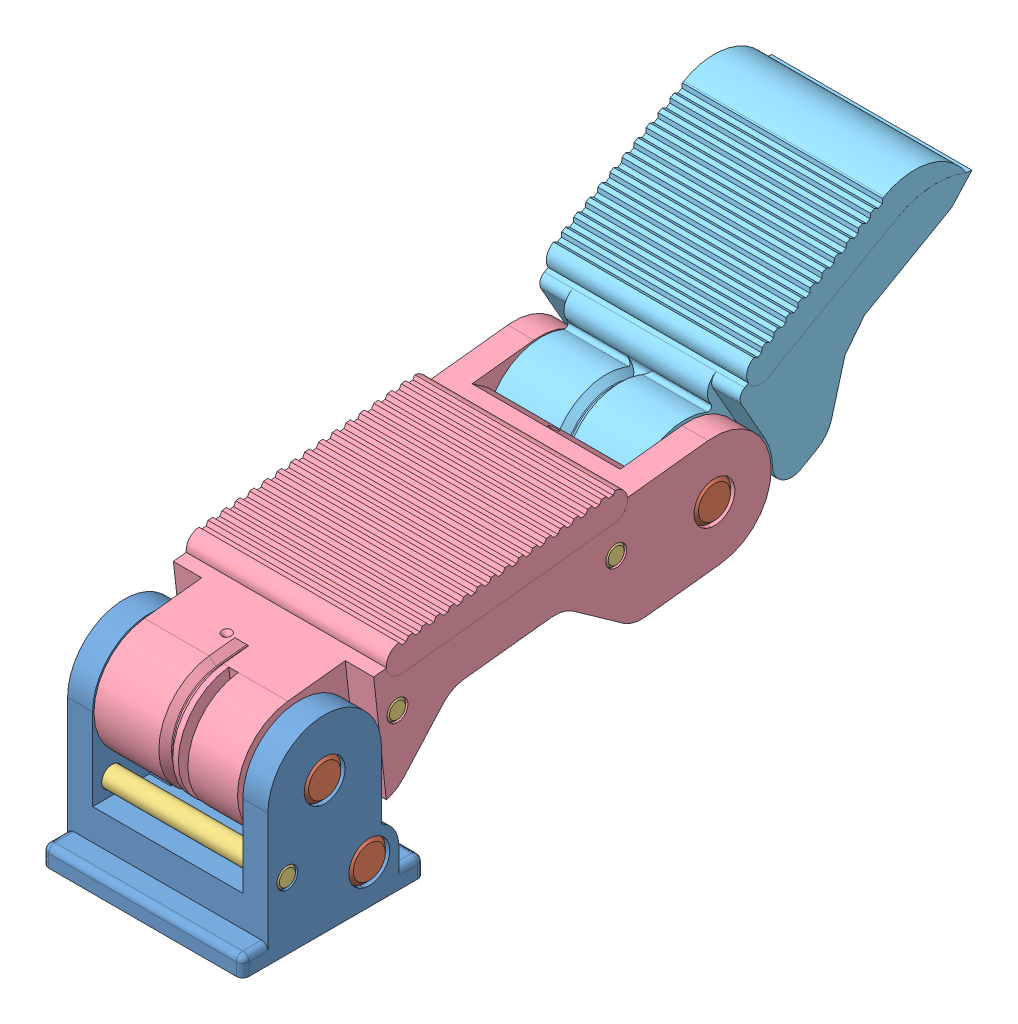
SolidWorks assembly block_finger_pp_t42, configuration Default. Lengths in mm.
Overall size (32.23 61.41 122.56).
15 component instances, 7 part files, 28 mates.
Components (placement in the parent):
- c1_t42-1: c1_t42 [Default] at origin size (31.75 29.94 28.75)
- 98381A544 D1-4 L5-4-1: 98381A544 D1-4 L5-4 [98381A544] at (0 20.9353 -30) size (31.75 6.35 6.35)
- 98381A544 D1-4 L5-4-2: 98381A544 D1-4 L5-4 [98381A544] at (0 6.175 -37.075) size (31.75 6.35 6.35)
- 98381A477 D1-8 L5-4-1: 98381A477 D1-8 L5-4 [98381A477] at (0 10.5228 -24.0875) size (31.75 3.17 3.17)
- t42_pp_A-1: t42_pp_A [Default] at (-0.325 20.9353 -30) x (1 0 0) z (0 -0.111473 0.993768) size (31.75 20.27 80.5)
- t42_pp_B-1: t42_pp_B [Default] at (-0.475 27.9023 -92.1105) x (1 0 0) z (0 -0.494638 0.869099) size (31.75 22.88 57.08)
- 98381A544 D1-4 L5-4-3: 98381A544 D1-4 L5-4 [98381A544] at (-0.325 27.9023 -92.1105) size (31.75 6.35 6.35)
- 98381A477 D1-8 L5-4-2: 98381A477 D1-8 L5-4 [98381A477] at (-0.325 24.4415 -41.8581) size (31.75 3.17 3.17)
- 98381A477 D1-8 L5-4-3: 98381A477 D1-8 L5-4 [98381A477] at (-0.325 28.3322 -76.5436) size (31.75 3.17 3.17)
- 93365A120 4-40 insert-1: 93365A120 4-40 insert [93365A120] at (-0.475 39.5312 -114.477) x (1 0 0) z (0 0.789576 -0.613653) size (4.37 3.82 4.37)
- 93365A120 4-40 insert-2: 93365A120 4-40 insert [93365A120] at (-0.475 22.7501 -101.253) x (-0.837169 0.270539 -0.475349) z (-0.546944 -0.414095 0.727583) size (4.37 3.82 4.37)
- 93365A120 4-40 insert-3: 93365A120 4-40 insert [93365A120] at (-0.325 17.6765 -81.6854) x (-0.837169 0.060969 -0.543535) z (-0.546944 -0.093321 0.831951) size (4.37 3.82 4.37)
- 91253A106 4-40 L1-4 countersunk-1: 91253A106 4-40 L1-4 countersunk [91253A106] at (-0.475 38.2295 -116.1519) x (1 0 0) z (0 -0.613653 -0.789576) size (6.48 6.48 6.63)
- 91253A106 4-40 L1-4 countersunk-2: 91253A106 4-40 L1-4 countersunk [91253A106] at (-0.475 20.9066 -102.3022) x (1 0 0) z (0 -0.869099 -0.494638) size (6.48 6.48 6.63)
- 91253A106 4-40 L1-4 countersunk-3: 91253A106 4-40 L1-4 countersunk [91253A106] at (-0.325 15.5685 -81.9219) x (1 0 0) z (0 -0.993768 -0.111473) size (6.48 6.48 6.63)
Mates (geometry in assembly coordinates):
- Concentric1: concentric aligned: cylinder of c1_t42-1 through (-15.875 20.9353 -30) axis (1 0 0) radius 3.25; cylinder of 98381A544 D1-4 L5-4-1 through (-15.875 20.9353 -30) axis (1 0 0) radius 3.175
- Coincident1: coincident aligned: plane of c1_t42-1 through (15.875 20.9353 -30) normal (1 0 0); plane of 98381A544 D1-4 L5-4-1 through (15.875 20.9353 -30) normal (1 0 0)
- Concentric2: concentric aligned: cylinder of c1_t42-1 through (-15.875 6.175 -37.075) axis (1 0 0) radius 3.25; cylinder of 98381A544 D1-4 L5-4-2 through (-15.875 6.175 -37.075) axis (1 0 0) radius 3.175
- Coincident2: coincident aligned: plane of c1_t42-1 through (15.875 20.9353 -30) normal (1 0 0); plane of 98381A544 D1-4 L5-4-2 through (15.875 6.175 -37.075) normal (1 0 0)
- Concentric3: concentric aligned: cylinder of c1_t42-1 through (-15.875 10.5228 -24.0875) axis (1 0 0) radius 1.6625; cylinder of 98381A477 D1-8 L5-4-1 through (-15.875 10.5228 -24.0875) axis (1 0 0) radius 1.5875
- Coincident3: coincident aligned: plane of c1_t42-1 through (15.875 20.9353 -30) normal (1 0 0); plane of 98381A477 D1-8 L5-4-1 through (15.875 10.5228 -24.0875) normal (1 0 0)
- Concentric4: concentric aligned: cylinder of 98381A544 D1-4 L5-4-1 through (-15.875 20.9353 -30) axis (1 0 0) radius 3.175; cylinder of t42_pp_A-1 through (-16.2 20.9353 -30) axis (1 0 0) radius 3.525
- Distance1: distance = 0.2 mm anti-aligned: plane of c1_t42-1 through (-11.9 20.9353 -30) normal (1 0 0); plane of t42_pp_A-1 through (-11.7 13.0113 -40.0962) normal (-1 0 0)
- Concentric5: concentric aligned: cylinder of t42_pp_A-1 through (-16.2 27.9023 -92.1105) axis (1 0 0) radius 3.25; cylinder of 98381A544 D1-4 L5-4-3 through (-16.2 27.9023 -92.1105) axis (1 0 0) radius 3.175
- Coincident5: coincident aligned: plane of t42_pp_A-1 through (15.55 20.9353 -30) normal (1 0 0); plane of 98381A544 D1-4 L5-4-3 through (15.55 27.9023 -92.1105) normal (1 0 0)
- Concentric6: concentric aligned: cylinder of t42_pp_B-1 through (-16.35 27.9023 -92.1105) axis (1 0 0) radius 3.525; cylinder of 98381A544 D1-4 L5-4-3 through (-16.2 27.9023 -92.1105) axis (1 0 0) radius 3.175
- Distance2: distance = 0.2 mm anti-aligned: plane of t42_pp_A-1 through (-12.05 27.9023 -92.1105) normal (1 0 0); plane of t42_pp_B-1 through (-11.85 27.9023 -92.1105) normal (-1 0 0)
- Concentric7: concentric aligned: cylinder of t42_pp_A-1 through (-16.2 24.4415 -41.8581) axis (1 0 0) radius 1.6625; cylinder of 98381A477 D1-8 L5-4-2 through (-16.2 24.4415 -41.8581) axis (1 0 0) radius 1.5875
- Coincident7: coincident aligned: plane of t42_pp_A-1 through (15.55 20.9353 -30) normal (1 0 0); plane of 98381A477 D1-8 L5-4-2 through (15.55 24.4415 -41.8581) normal (1 0 0)
- Concentric8: concentric aligned: cylinder of t42_pp_A-1 through (-16.2 28.3322 -76.5436) axis (1 0 0) radius 1.6625; cylinder of 98381A477 D1-8 L5-4-3 through (-16.2 28.3322 -76.5436) axis (1 0 0) radius 1.5875
- Coincident8: coincident aligned: plane of t42_pp_A-1 through (15.55 20.9353 -30) normal (1 0 0); plane of 98381A477 D1-8 L5-4-3 through (15.55 28.3322 -76.5436) normal (1 0 0)
- Concentric9: concentric aligned: cylinder of t42_pp_A-1 through (-0.325 22.1484 -81.1838) axis (0 -0.993768 -0.111473) radius 1.85; circle of 93365A120 4-40 insert-3
- Coincident9: coincident aligned: plane of t42_pp_A-1 through (15.55 11.9914 -31.0033) normal (0 -0.993768 -0.111473); plane of 93365A120 4-40 insert-3 through (-0.325 17.6765 -81.6854) normal (0 -0.993768 -0.111473)
- Concentric10: concentric aligned: cylinder of t42_pp_B-1 through (-0.475 26.2265 -99.2744) axis (0 -0.869099 -0.494638) radius 1.85; circle of 93365A120 4-40 insert-2
- Coincident10: coincident aligned: plane of t42_pp_B-1 through (15.4 20.0804 -96.5622) normal (0 -0.869099 -0.494638); plane of 93365A120 4-40 insert-2 through (-0.475 22.7501 -101.253) normal (0 -0.869099 -0.494638)
- Concentric11: concentric aligned: cylinder of t42_pp_B-1 through (-0.475 42.2926 -110.9239) axis (0 -0.613653 -0.789576) radius 1.85; circle of 93365A120 4-40 insert-1
- Coincident11: coincident aligned: plane of t42_pp_B-1 through (-21.35 41.5051 -116.0112) normal (0 -0.613653 -0.789576); plane of 93365A120 4-40 insert-1 through (-0.475 39.5312 -114.477) normal (0 -0.613653 -0.789576)
- Concentric12: concentric anti-aligned: circle of 93365A120 4-40 insert-1; circle of 91253A106 4-40 L1-4 countersunk-1
- Coincident12: coincident: circle of 93365A120 4-40 insert-1; cone of 91253A106 4-40 L1-4 countersunk-1 through (-0.475 39.5232 -114.4873) axis (0 0.613653 0.789576)
- Concentric13: concentric anti-aligned: circle of 93365A120 4-40 insert-2; circle of 91253A106 4-40 L1-4 countersunk-2
- Coincident13: coincident: circle of 93365A120 4-40 insert-2; cylinder of 91253A106 4-40 L1-4 countersunk-2 through (-0.475 22.7388 -101.2594) axis (0 0.869099 0.494638) radius 715.585
- Concentric14: concentric anti-aligned: circle of 93365A120 4-40 insert-3; circle of 91253A106 4-40 L1-4 countersunk-3
- Coincident14: coincident: circle of 93365A120 4-40 insert-3; cone of 91253A106 4-40 L1-4 countersunk-3 through (-0.325 17.6636 -81.6868) axis (0 0.993768 0.111473)
